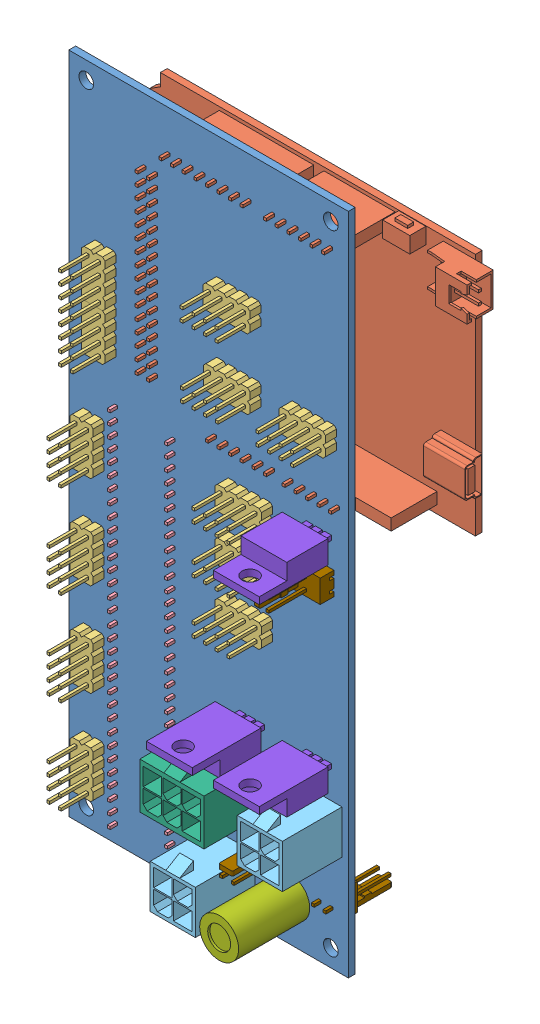
SolidWorks assembly Mainboard assy, configuration По умолчанию. Lengths in mm.
Overall size (83.26 153.54 38.5).
31 component instances, 12 part files, 62 mates.
Components (placement in the parent):
- Mainboard-1: Mainboard [По умолчанию] at (-0.1794 -4.7543 0) size (60.96 144.78 1.5)
- Seeeduino Mega  (ATMEGA1280)-2: Seeeduino Mega  (ATMEGA1280) [По умолчанию] at (9.9671 39.2598 -12.5) x (0 1 0) z (0 0 1) size (53.71 74.96 17.3)
- Pin header - 8 pin-1: Pin header - 8 pin [По умолчанию] at (-25.4931 -64.4585 1.5) size (5.08 10.16 11.5)
- Pin header - 8 pin-2: Pin header - 8 pin [По умолчанию] at (-25.4931 -44.0368 1.5) size (5.08 10.16 11.5)
- Pin header - 8 pin-3: Pin header - 8 pin [По умолчанию] at (-25.4931 -23.7281 1.5) size (5.08 10.16 11.5)
- Pin header - 8 pin-4: Pin header - 8 pin [По умолчанию] at (-25.4931 -3.4612 1.5) size (5.08 10.16 11.5)
- Pin header - 8 pin-5: Pin header - 8 pin [По умолчанию] at (8.6776 1.6656 1.5) x (0 -1 0) z (0 0 1) size (5.08 10.16 11.5)
- Pin header - 8 pin-6: Pin header - 8 pin [По умолчанию] at (8.6776 -8.4579 1.5) x (0 -1 0) z (0 0 1) size (5.08 10.16 11.5)
- Pin header - 8 pin-7: Pin header - 8 pin [По умолчанию] at (8.6776 -19.9047 1.5) x (0 -1 0) z (0 0 1) size (5.08 10.16 11.5)
- Pin header - 8 pin-8: Pin header - 8 pin [По умолчанию] at (-22.9085 29.5446 1.5) size (5.08 10.16 11.5)
- Pin header - 8 pin-9: Pin header - 8 pin [По умолчанию] at (-22.9085 19.3846 1.5) size (5.08 10.16 11.5)
- Pin header - 8 pin-10: Pin header - 8 pin [По умолчанию] at (6.1844 23.198 1.5) x (0 -1 0) z (0 0 1) size (5.08 10.16 11.5)
- Pin header - 8 pin-11: Pin header - 8 pin [По умолчанию] at (22.6219 23.198 1.5) x (0 -1 0) z (0 0 1) size (5.08 10.16 11.5)
- Pin header - 8 pin-12: Pin header - 8 pin [По умолчанию] at (6.1239 38.4096 1.5) x (0 -1 0) z (0 0 1) size (5.08 10.16 11.5)
- A4988-1: A4988 [По умолчанию] at (-14.0853 -3.3163 -11) x (-1 0 0) z (0 0 -1) size (15.3 20.4 17.4)
- A4988-2: A4988 [По умолчанию] at (-14.0853 -23.691 -11) x (-1 0 0) z (0 0 -1) size (15.3 20.4 17.4)
- A4988-3: A4988 [По умолчанию] at (-14.0853 -44.0854 -11) x (-1 0 0) z (0 0 -1) size (15.3 20.4 17.4)
- A4988-4: A4988 [По умолчанию] at (-14.0853 -64.3915 -11) x (-1 0 0) z (0 0 -1) size (15.3 20.4 17.4)
- MF-4 MA-1: MF-4 MA [По умолчанию] at (23.9935 -50.2825 1.5) x (0 1 0) z (1 0 0) size (11.3 16 9.84)
- MF-4 MA-2: MF-4 MA [По умолчанию] at (5.016 -68.4522 1.5) x (0 1 0) z (1 0 0) size (11.3 16 9.84)
- MF-6 MA-2: MF-6 MA [По умолчанию] at (4.8251 -50.5325 1.5) x (0 1 0) z (1 0 0) size (11.8 16 14)
- 100mF16V-1: 100mF16V [По умолчанию] at (17.6296 -68.1455 1.5) size (8.5 8.5 15.5)
- IRL3803-1: IRL3803 [По умолчанию] at (4.2668 -36.4417 12) x (1 0 0) z (0 -1 0) size (10 20.7 5)
- IRL3803-2: IRL3803 [По умолчанию] at (18.875 -36.4904 12) x (1 0 0) z (0 -1 0) size (10 20.7 5)
- IRL3803-3: IRL3803 [По умолчанию] at (28.8731 1.6355 12) x (-1 0 0) z (0 1 0) size (10 20.7 5)
- Fan 2-pin connector-1: Fan 2-pin connector [По умолчанию] at (15.0145 -58.1476 7.25) x (1 0 0) z (0 -1 0) size (5 14.5 5.8)
- Fan 2-pin connector-2: Fan 2-pin connector [По умолчанию] at (21.3633 -4.2025 7.25) x (0 1 0) z (1 0 0) size (5 14.5 5.8)
- Fan 2-pin connector-3: Fan 2-pin connector [По умолчанию] at (25.3341 -68.23 -5.75) x (1 0 0) z (0 1 0) size (5 14.5 5.8)
- Polulu radiator-1: Polulu radiator [По умолчанию] at (-14.2113 -23.4788 -16) x (-1 0 0) z (0 0 -1) size (64.16 92 3) (hidden)
- Polulu radiator left support-1: Polulu radiator left support [По умолчанию] at (-30.6594 -4.7543 0) x (0 0 1) z (-1 0 0) size (12.5 71.22 9.07)
- Polulu right support-1: Polulu right support [По умолчанию] at (-6.5853 -64.3915 -11) x (0 0 -1) z (1 0 0) size (12.5 71.22 7)
Mates (geometry in assembly coordinates):
- Параллельность1: parallel: plane of Mainboard-1 through (30.3006 -77.1443 1.5) normal (1 0 0); plane of Seeeduino Mega  (ATMEGA1280)-2 through (45.4971 7.6548 -11) normal (1 0 0)
- Совпадение2: coincident anti-aligned: plane of Mainboard-1 through (-30.6594 67.6357 0) normal (0 0 -1); plane of Seeeduino Mega  (ATMEGA1280)-2 through (16.5371 9.4048 0) normal (0 0 1)
- Совпадение3: coincident aligned: plane of Pin header - 8 pin-11 through (13.6451 23.198 1.5) normal (0 0 -1); plane of Pin header - 8 pin-12 through (-2.8529 38.4096 1.5) normal (0 0 -1)
- Совпадение4: coincident aligned: plane of Pin header - 8 pin-10 through (-2.7924 23.198 1.5) normal (0 0 -1); plane of Pin header - 8 pin-11 through (13.6451 23.198 1.5) normal (0 0 -1)
- Совпадение5: coincident aligned: plane of Pin header - 8 pin-4 through (-25.4931 -12.438 1.5) normal (0 0 -1); plane of Pin header - 8 pin-10 through (-2.7924 23.198 1.5) normal (0 0 -1)
- Совпадение6: coincident aligned: plane of Pin header - 8 pin-3 through (-25.4931 -32.7049 1.5) normal (0 0 -1); plane of Pin header - 8 pin-4 through (-25.4931 -12.438 1.5) normal (0 0 -1)
- Совпадение7: coincident aligned: plane of Pin header - 8 pin-2 through (-25.4931 -53.0137 1.5) normal (0 0 -1); plane of Pin header - 8 pin-3 through (-25.4931 -32.7049 1.5) normal (0 0 -1)
- Совпадение8: coincident aligned: plane of Pin header - 8 pin-1 through (-25.4931 -73.4354 1.5) normal (0 0 -1); plane of Pin header - 8 pin-2 through (-25.4931 -53.0137 1.5) normal (0 0 -1)
- Совпадение9: coincident aligned: plane of Pin header - 8 pin-3 through (-22.9531 -32.7049 3.9) normal (1 0 0); plane of Pin header - 8 pin-4 through (-22.9531 -12.438 3.9) normal (1 0 0)
- Совпадение10: coincident aligned: plane of Pin header - 8 pin-2 through (-22.9531 -53.0137 3.9) normal (1 0 0); plane of Pin header - 8 pin-3 through (-22.9531 -32.7049 3.9) normal (1 0 0)
- Совпадение11: coincident aligned: plane of Pin header - 8 pin-1 through (-22.9531 -73.4354 3.9) normal (1 0 0); plane of Pin header - 8 pin-2 through (-22.9531 -53.0137 3.9) normal (1 0 0)
- Совпадение12: coincident anti-aligned: plane of Mainboard-1 through (-30.6594 67.6357 1.5) normal (0 0 1); plane of Pin header - 8 pin-3 through (-25.4931 -32.7049 1.5) normal (0 0 -1)
- Совпадение13: coincident aligned: plane of Pin header - 8 pin-5 through (-0.2993 1.6656 1.5) normal (0 0 -1); plane of Pin header - 8 pin-10 through (-2.7924 23.198 1.5) normal (0 0 -1)
- Совпадение14: coincident aligned: plane of Pin header - 8 pin-5 through (-0.2993 1.6656 1.5) normal (0 0 -1); plane of Pin header - 8 pin-6 through (-0.2993 -8.4579 1.5) normal (0 0 -1)
- Совпадение15: coincident aligned: plane of Pin header - 8 pin-6 through (-0.2993 -8.4579 1.5) normal (0 0 -1); plane of Pin header - 8 pin-7 through (-0.2993 -19.9047 1.5) normal (0 0 -1)
- Совпадение16: coincident aligned: plane of Pin header - 8 pin-4 through (-25.4931 -12.438 1.5) normal (0 0 -1); plane of Pin header - 8 pin-9 through (-22.9085 10.4077 1.5) normal (0 0 -1)
- Совпадение17: coincident aligned: plane of Pin header - 8 pin-8 through (-22.9085 20.5677 1.5) normal (0 0 -1); plane of Pin header - 8 pin-9 through (-22.9085 10.4077 1.5) normal (0 0 -1)
- Параллельность2: parallel aligned: plane of Pin header - 8 pin-8 through (-20.3685 20.5677 3.9) normal (1 0 0); plane of Pin header - 8 pin-9 through (-20.3685 10.4077 3.9) normal (1 0 0)
- Параллельность5: parallel anti-aligned: plane of Pin header - 8 pin-10 through (-2.7924 25.738 3.9) normal (0 1 0); plane of Pin header - 8 pin-12 through (-2.8529 35.8696 3.9) normal (0 -1 0)
- Параллельность6: parallel anti-aligned: plane of Pin header - 8 pin-11 through (13.6451 20.658 3.9) normal (0 -1 0); plane of Pin header - 8 pin-12 through (-2.8529 40.9496 3.9) normal (0 1 0)
- Параллельность7: parallel anti-aligned: plane of Pin header - 8 pin-5 through (-0.2993 -0.8744 3.9) normal (0 -1 0); plane of Pin header - 8 pin-11 through (13.6451 25.738 3.9) normal (0 1 0)
- Параллельность8: parallel anti-aligned: plane of Pin header - 8 pin-5 through (-0.2993 4.2056 3.9) normal (0 1 0); plane of Pin header - 8 pin-6 through (-0.2993 -10.9979 3.9) normal (0 -1 0)
- Параллельность9: parallel anti-aligned: plane of Pin header - 8 pin-6 through (-0.2993 -5.9179 3.9) normal (0 1 0); plane of Pin header - 8 pin-7 through (-0.2993 -22.4447 3.9) normal (0 -1 0)
- Совпадение26: coincident aligned: plane of Pin header - 8 pin-10 through (-2.7924 25.738 3.9) normal (0 1 0); plane of Pin header - 8 pin-11 through (13.6451 25.738 3.9) normal (0 1 0)
- Совпадение27: coincident aligned: plane of Pin header - 8 pin-5 through (13.7576 1.6656 3.9) normal (1 0 0); plane of Pin header - 8 pin-6 through (13.7576 -8.4579 3.9) normal (1 0 0)
- Совпадение28: coincident aligned: plane of Pin header - 8 pin-6 through (13.7576 -8.4579 3.9) normal (1 0 0); plane of Pin header - 8 pin-7 through (13.7576 -19.9047 3.9) normal (1 0 0)
- Совпадение29: coincident aligned: plane of A4988-1 through (-21.5853 6.6837 0) normal (-1 0 0); plane of A4988-2 through (-21.5853 -13.691 0) normal (-1 0 0)
- Совпадение30: coincident aligned: plane of A4988-2 through (-21.5853 -13.691 0) normal (-1 0 0); plane of A4988-3 through (-21.5853 -34.0854 0) normal (-1 0 0)
- Совпадение31: coincident aligned: plane of A4988-3 through (-21.5853 -34.0854 0) normal (-1 0 0); plane of A4988-4 through (-21.5853 -54.3915 0) normal (-1 0 0)
- Совпадение32: coincident aligned: plane of A4988-3 through (-21.5853 -54.0854 0) normal (0 0 1); plane of A4988-4 through (-21.5853 -74.3915 0) normal (0 0 1)
- Совпадение33: coincident aligned: plane of A4988-2 through (-21.5853 -33.691 0) normal (0 0 1); plane of A4988-3 through (-21.5853 -54.0854 0) normal (0 0 1)
- Совпадение34: coincident aligned: plane of A4988-1 through (-6.5853 -13.3163 0) normal (0 0 1); plane of A4988-2 through (-6.5853 -33.691 0) normal (0 0 1)
- Совпадение36: coincident anti-aligned: plane of Mainboard-1 through (-30.6594 67.6357 0) normal (0 0 -1); plane of A4988-1 through (-6.5853 -13.3163 0) normal (0 0 1)
- Параллельность10: parallel aligned: plane of Mainboard-1 through (-30.6594 -77.1443 1.5) normal (-1 0 0); plane of A4988-1 through (-21.5853 6.6837 0) normal (-1 0 0)
- Параллельность12: parallel anti-aligned: plane of Mainboard-1 through (-30.6594 -77.1443 1.5) normal (-1 0 0); plane of Pin header - 8 pin-9 through (-20.3685 10.4077 3.9) normal (1 0 0)
- Совпадение40: coincident anti-aligned: plane of Pin header - 8 pin-8 through (-22.9085 24.4646 3.9) normal (0 -1 0); plane of Pin header - 8 pin-9 through (-22.9085 24.4646 3.9) normal (0 1 0)
- Совпадение41: coincident aligned: plane of Pin header - 8 pin-8 through (-25.4485 20.5677 3.9) normal (-1 0 0); plane of Pin header - 8 pin-9 through (-25.4485 10.4077 3.9) normal (-1 0 0)
- Совпадение42: coincident aligned: plane of MF-4 MA-1 through (23.9935 -61.399 1.5) normal (0 0 -1); plane of MF-6 MA-2 through (4.8251 -64.056 1.5) normal (0 0 -1)
- Совпадение43: coincident aligned: plane of MF-4 MA-1 through (23.9935 -45.5325 14.5) normal (0 1 0); plane of MF-6 MA-2 through (4.8251 -45.5325 14.5) normal (0 1 0)
- Совпадение44: coincident aligned: plane of MF-4 MA-1 through (23.9935 -61.399 1.5) normal (0 0 -1); plane of MF-4 MA-2 through (5.016 -79.5687 1.5) normal (0 0 -1)
- Совпадение45: coincident anti-aligned: plane of Mainboard-1 through (-30.6594 67.6357 1.5) normal (0 0 1); plane of MF-4 MA-1 through (23.9935 -61.399 1.5) normal (0 0 -1)
- Параллельность13: parallel aligned: plane of Mainboard-1 through (30.3006 -77.1443 1.5) normal (1 0 0); plane of MF-6 MA-2 through (11.8251 -64.056 14.5) normal (1 0 0)
- Параллельность14: parallel aligned: plane of MF-4 MA-2 through (5.016 -73.2022 14.5) normal (0 -1 0); plane of MF-6 MA-2 through (4.8251 -55.5325 14.5) normal (0 -1 0)
- Совпадение48: coincident anti-aligned: plane of Mainboard-1 through (-30.6594 67.6357 1.5) normal (0 0 1); plane of 100mF16V-1 through (17.6296 -68.1455 1.5) normal (0 0 -1)
- Совпадение49: coincident aligned: plane of IRL3803-1 through (10.5168 -39.4417 1.5) normal (0 0 -1); plane of IRL3803-2 through (25.125 -39.4904 1.5) normal (0 0 -1)
- Совпадение50: coincident aligned: plane of IRL3803-2 through (25.125 -39.4904 1.5) normal (0 0 -1); plane of IRL3803-3 through (22.6231 4.6355 1.5) normal (0 0 -1)
- Совпадение51: coincident anti-aligned: plane of Mainboard-1 through (-30.6594 67.6357 1.5) normal (0 0 1); plane of IRL3803-3 through (22.6231 4.6355 1.5) normal (0 0 -1)
- Параллельность15: parallel aligned: plane of Mainboard-1 through (30.3006 -77.1443 1.5) normal (0 -1 0); plane of IRL3803-3 through (18.8731 1.6355 19.5) normal (0 -1 0)
- Совпадение52: coincident aligned: plane of Fan 2-pin connector-1 through (17.5145 -63.9476 1.5) normal (0 0 -1); plane of Fan 2-pin connector-2 through (27.1633 -1.7025 1.5) normal (0 0 -1)
- Совпадение53: coincident anti-aligned: plane of Mainboard-1 through (-30.6594 67.6357 1.5) normal (0 0 1); plane of Fan 2-pin connector-1 through (17.5145 -63.9476 1.5) normal (0 0 -1)
- Параллельность16: parallel aligned: plane of Mainboard-1 through (30.3006 -77.1443 1.5) normal (1 0 0); plane of Fan 2-pin connector-2 through (27.1633 -6.7025 13) normal (1 0 0)
- Совпадение55: coincident anti-aligned: plane of Mainboard-1 through (-30.6594 67.6357 0) normal (0 0 -1); plane of Fan 2-pin connector-3 through (27.8341 -62.43 0) normal (0 0 1)
- Параллельность17: parallel: line of Mainboard-1 through (-30.6594 67.6357 1.5) axis (0 -1 0); plane of Polulu radiator-1 through (-33.8613 9.096 -19) normal (-1 0 0)
- На месте1: in place: plane of Mainboard-1 through (-30.6594 -77.1443 1.5) normal (-1 0 0); plane of ? through (-30.6594 0 0) normal (-1 0 0); moOrthogonalPlaneRef_w of Mainboard-1 through (-30.6594 -77.1443 1.5) normal (-1 0 0); line of ? through (-55 -30.6594 0) axis (0 0 1); plane of Mainboard-1 through (-30.6594 -77.1443 1.5) normal (-1 0 0); plane of ? through (-30.6594 0 0) normal (0 0 1); plane of Mainboard-1 through (-30.6594 -77.1443 1.5) normal (-1 0 0); unknown of Polulu radiator left support-1
- Совпадение60: coincident aligned: plane of Mainboard-1; plane of Polulu radiator left support-1
- Совпадение61: coincident aligned: moOrthogonalPlaneRef_w of Mainboard-1 through (-30.6594 -4.7543 0) normal (0 1 0); plane of Polulu radiator left support-1
- Совпадение62: coincident anti-aligned: moOrthogonalPlaneRef_w of Mainboard-1 through (-30.6594 -4.7543 0) normal (0 0 -1); plane of Polulu radiator left support-1 through (-30.6594 -4.7543 0) normal (0 0 1)
- Совпадение60: coincident: plane of Polulu radiator-1 through (-15.2613 -72.304 -16) normal (0 0 1); plane of Polulu radiator left support-1 through (51.4072 -69.5685 -16) normal (0 0 -1)
- На месте2: in place: plane of A4988-4 through (-6.5853 -54.3915 0) normal (1 0 0); plane of ? through (-6.5853 0 0) normal (1 0 0); plane of A4988-4 through (-6.5853 -54.3915 0) normal (1 0 0); line of ? through (-55 -6.5853 0) axis (0 0 1); plane of A4988-4 through (-6.5853 -54.3915 0) normal (1 0 0); plane of ? through (-6.5853 0 0) normal (0 0 -1); plane of A4988-4 through (-6.5853 -54.3915 0) normal (1 0 0); unknown of Polulu right support-1
- Совпадение61: coincident aligned: plane of A4988-4; plane of Polulu right support-1
- Совпадение62: coincident aligned: moOrthogonalPlaneRef_w of A4988-4 through (-6.5853 -64.3915 -11) normal (0 1 0); plane of Polulu right support-1
- Совпадение63: coincident anti-aligned: moOrthogonalPlaneRef_w of A4988-4 through (-6.5853 -64.3915 -11) normal (0 0 1); plane of Polulu right support-1 through (-6.5853 -64.3915 -11) normal (0 0 -1)
